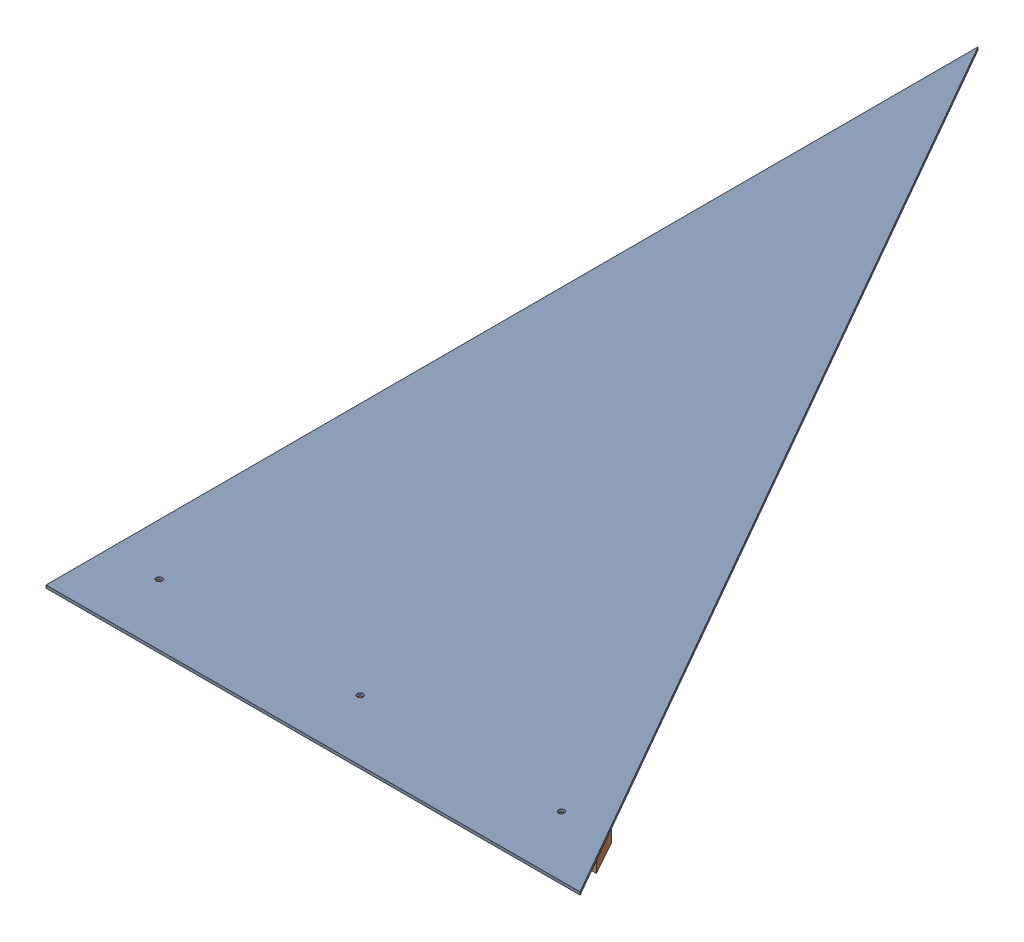
SolidWorks assembly GE-16188_ASM, configuration Default. Lengths in mm.
Overall size (605.76 22.23 1059.46).
2 component instances, 2 part files, 0 mates.
Components (placement in the parent):
- GE-16144-1: GE-16144 [Default] at origin size (605.76 3.17 1059.46)
- GE-16181-1: GE-16181 [Default] at (0 -19.05 1008.5242) x (1 0 0) z (0 1 0) size (574.68 38.1 19.05)
